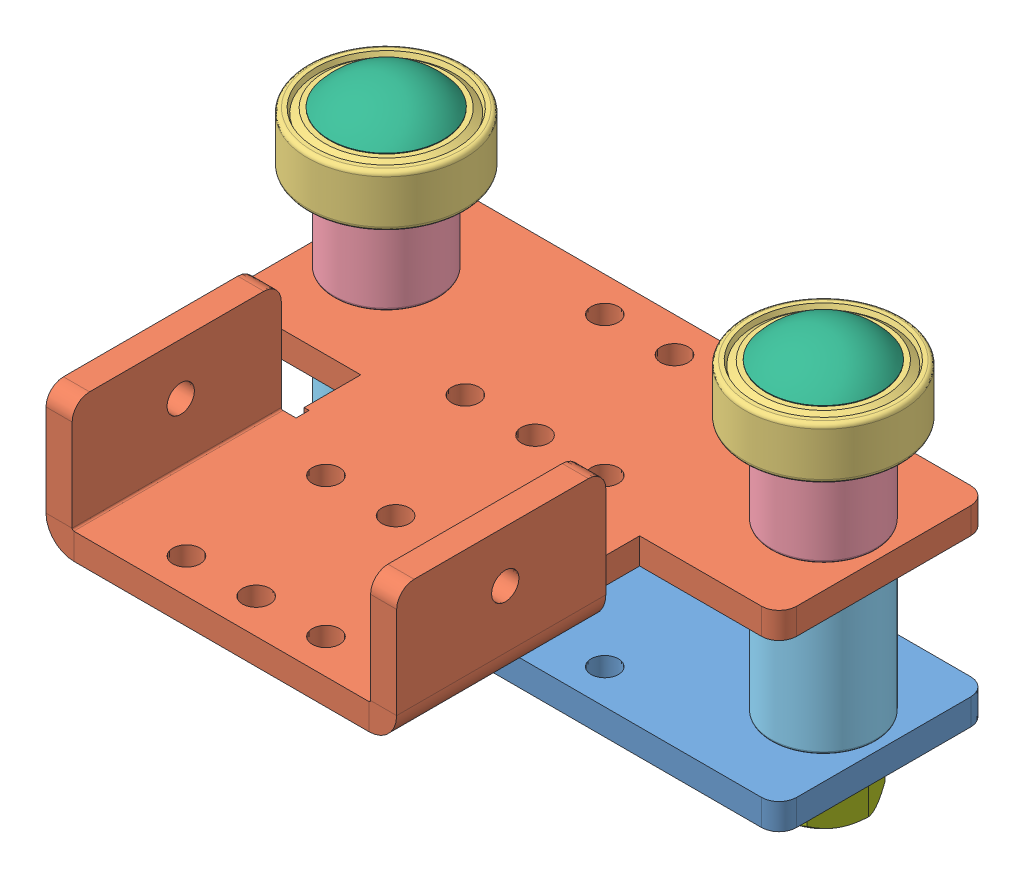
SolidWorks assembly Roller, configuration Défaut. Lengths in mm.
Overall size (108.2 74.88 88.9).
12 component instances, 7 part files, 35 mates.
Components (placement in the parent):
- am3793a-1: am3793a [Défaut] at (0 -30.16 0) size (101.6 4.76 38.1)
- am3794a-1: am3794a [Défaut] at origin size (101.6 25 88.9)
- am-0209b-1: am-0209b [Défaut] at (-39.8145 20.6375 0) x (1 0 0) z (0 1 0) size (28.57 28.57 9.53)
- am1451-1: am1451 [Défaut] at (-39.8145 7.9375 0) x (0 0 1) z (-1 0 0) size (19.05 15.88 19.05)
- am1451-2: am1451 [Défaut] at (39.8145 7.9375 0) x (-1 0 0) z (0 0 -1) size (19.05 15.88 19.05)
- am-0209b-3: am-0209b [Défaut] at (39.8145 20.6375 0) x (1 0 0) z (0 1 0) size (28.57 28.57 9.53)
- am1450-1: am1450 [Défaut] at (-39.8145 -17.46 0) size (19.05 25.4 19.05)
- am1450-2: am1450 [Défaut] at (39.8145 -17.46 0) size (19.05 25.4 19.05)
- round head bolt_ai-2: round head bolt_ai [RHBOLT 0.375-16x2.75x1-C] at (-39.8145 30.4292 0) x (0 -1 0) z (-1 0 0) size (74.88 20.65 20.65)
- round head bolt_ai-3: round head bolt_ai [RHBOLT 0.375-16x2.75x1-C] at (39.8145 30.4292 0) x (0 -1 0) z (-1 0 0) size (74.88 20.65 20.65)
- hex nut_ai-1: hex nut_ai [HNUT 0.3750-16-D-N] at (39.8145 -43.4798 0) x (0 0 1) z (0 -1 0) size (14.27 16.48 8.56)
- hex nut_ai-2: hex nut_ai [HNUT 0.3750-16-D-N] at (-39.8145 -43.4798 0) x (0 0 1) z (0 -1 0) size (14.27 16.48 8.56)
Mates (geometry in assembly coordinates):
- Coaxiale1: concentric aligned: cylinder of am3793a-1 through (-39.8145 -34.92 0) axis (0 1 0) radius 4.7625; cylinder of am3794a-1 through (-39.8145 -4.76 0) axis (0 1 0) radius 4.7625
- Coïncidente1: coincident aligned: plane of am3793a-1 through (50.8 -34.92 -19.05) normal (0 0 -1); plane of am3794a-1 through (50.8 -4.76 -19.05) normal (0 0 -1)
- Coaxiale3: concentric anti-aligned: cylinder of am3794a-1 through (-39.8145 -4.76 0) axis (0 1 0) radius 4.7625; cylinder of am1451-1 through (-39.8145 15.875 0) axis (0 -1 0) radius 4.8514
- Coïncidente2: coincident anti-aligned: plane of am3794a-1 through (0 0 0) normal (0 1 0); plane of am1451-1 through (-39.8145 0 0) normal (0 -1 0)
- Coïncidente3: coincident aligned: plane of am3794a-1 through (0 0 0) normal (0 0 1); plane of assembly through (0 0 0) normal (0 0 1)
- Coïncidente4: coincident aligned: plane of am3794a-1 through (0 0 0) normal (0 1 0); plane of assembly through (0 0 0) normal (0 1 0)
- Coïncidente5: coincident aligned: plane of am3794a-1 through (0 0 0) normal (1 0 0); plane of assembly through (0 0 0) normal (1 0 0)
- Parallèle1: parallel anti-aligned: plane of am1451-1 through (-39.8145 7.9375 0) normal (-1 0 0); plane of assembly through (0 0 0) normal (1 0 0)
- Coaxiale6: concentric anti-aligned: cylinder of am3794a-1 through (39.8145 -4.76 0) axis (0 1 0) radius 4.7625; cylinder of am1451-2 through (39.8145 15.875 0) axis (0 -1 0) radius 4.8514
- Coïncidente7: coincident anti-aligned: plane of am3794a-1 through (0 0 0) normal (0 1 0); plane of am1451-2 through (39.8145 0 0) normal (0 -1 0)
- Parallèle2: parallel anti-aligned: plane of am1451-2 through (39.8145 7.9375 0) normal (-1 0 0); plane of assembly through (0 0 0) normal (1 0 0)
- Coaxiale7: concentric anti-aligned: cylinder of am-0209b-1 through (-39.8145 15.8737 0) axis (0 1 0) radius 4.7625; cylinder of am1451-1 through (-39.8145 15.875 0) axis (0 -1 0) radius 4.8514
- Coïncidente9: coincident anti-aligned: plane of am-0209b-1 through (-28.5904 15.875 0) normal (0 -1 0); plane of am1451-1 through (-39.8145 15.875 0) normal (0 1 0)
- Parallèle3: parallel aligned: plane of am-0209b-1 through (-39.8145 20.6375 0) normal (1 0 0); plane of assembly through (0 0 0) normal (1 0 0)
- Coaxiale8: concentric anti-aligned: cylinder of am1451-2 through (39.8145 15.875 0) axis (0 -1 0) radius 4.8514; cylinder of am-0209b-3 through (39.8145 15.8737 0) axis (0 1 0) radius 4.7625
- Coïncidente11: coincident anti-aligned: plane of am1451-2 through (39.8145 15.875 0) normal (0 1 0); plane of am-0209b-3 through (51.0386 15.875 0) normal (0 -1 0)
- Parallèle4: parallel aligned: plane of am-0209b-3 through (39.8145 20.6375 0) normal (1 0 0); plane of assembly through (0 0 0) normal (1 0 0)
- Coaxiale9: concentric anti-aligned: cylinder of am3794a-1 through (-39.8145 -4.76 0) axis (0 1 0) radius 4.7625; cylinder of am1450-1 through (-39.8145 -4.76 0) axis (0 -1 0) radius 4.8514
- Coïncidente12: coincident anti-aligned: plane of am3794a-1 through (0 -4.76 0) normal (0 -1 0); plane of am1450-1 through (-39.8145 -4.76 0) normal (0 1 0)
- Parallèle5: parallel aligned: plane of am1450-1 through (-39.8145 -17.46 0) normal (1 0 0); plane of assembly through (0 0 0) normal (1 0 0)
- Coaxiale10: concentric anti-aligned: cylinder of am3794a-1 through (39.8145 -4.76 0) axis (0 1 0) radius 4.7625; cylinder of am1450-2 through (39.8145 -4.76 0) axis (0 -1 0) radius 4.8514
- Coïncidente14: coincident anti-aligned: plane of am3794a-1 through (0 -4.76 0) normal (0 -1 0); plane of am1450-2 through (39.8145 -4.76 0) normal (0 1 0)
- Parallèle6: parallel aligned: plane of am1450-2 through (39.8145 -17.46 0) normal (1 0 0); plane of assembly through (0 0 0) normal (1 0 0)
- Coïncidente15: coincident anti-aligned: plane of am3793a-1 through (0 -30.16 0) normal (0 1 0); plane of am1450-1 through (-39.8145 -30.16 0) normal (0 -1 0)
- Coaxiale11: concentric aligned: cylinder of am-0209b-1 through (-39.8145 15.8737 0) axis (0 1 0) radius 4.7625; cylinder of round head bolt_ai-2 through (-39.8145 30.4292 0) axis (0 1 0) radius 4.7625
- Coïncidente16: coincident anti-aligned: plane of am-0209b-1 through (-31.8624 25.4 0) normal (0 1 0); plane of round head bolt_ai-2 through (-39.8145 25.4 10.3251) normal (0 -1 0)
- Parallèle7: parallel anti-aligned: plane of round head bolt_ai-2 through (-39.8145 30.4292 0) normal (-1 0 0); plane of assembly through (0 0 0) normal (1 0 0)
- Coaxiale12: concentric aligned: cylinder of am-0209b-3 through (39.8145 15.8737 0) axis (0 1 0) radius 4.7625; cylinder of round head bolt_ai-3 through (39.8145 30.4292 0) axis (0 1 0) radius 4.7625
- Coïncidente18: coincident anti-aligned: plane of am-0209b-3 through (47.7666 25.4 0) normal (0 1 0); plane of round head bolt_ai-3 through (39.8145 25.4 10.3251) normal (0 -1 0)
- Parallèle8: parallel anti-aligned: plane of round head bolt_ai-3 through (39.8145 30.4292 0) normal (-1 0 0); plane of assembly through (0 0 0) normal (1 0 0)
- Coaxiale13: concentric anti-aligned: cylinder of round head bolt_ai-3 through (39.8145 30.4292 0) axis (0 1 0) radius 4.7625; cylinder of hex nut_ai-1 through (39.8145 -34.92 0) axis (0 -1 0) radius 3.9688
- Coïncidente19: coincident anti-aligned: plane of am3793a-1 through (0 -34.92 0) normal (0 -1 0); plane of hex nut_ai-1 through (31.5729 -34.92 0) normal (0 1 0)
- Parallèle10: parallel anti-aligned: plane of hex nut_ai-1 through (39.8145 -43.4798 0) normal (-1 0 0); plane of assembly through (0 0 0) normal (1 0 0)
- Coaxiale14: concentric anti-aligned: cylinder of round head bolt_ai-2 through (-39.8145 30.4292 0) axis (0 1 0) radius 4.7625; cylinder of hex nut_ai-2 through (-39.8145 -34.92 0) axis (0 -1 0) radius 3.9688
- Coïncidente21: coincident anti-aligned: plane of am3793a-1 through (0 -34.92 0) normal (0 -1 0); plane of hex nut_ai-2 through (-48.0561 -34.92 0) normal (0 1 0)
